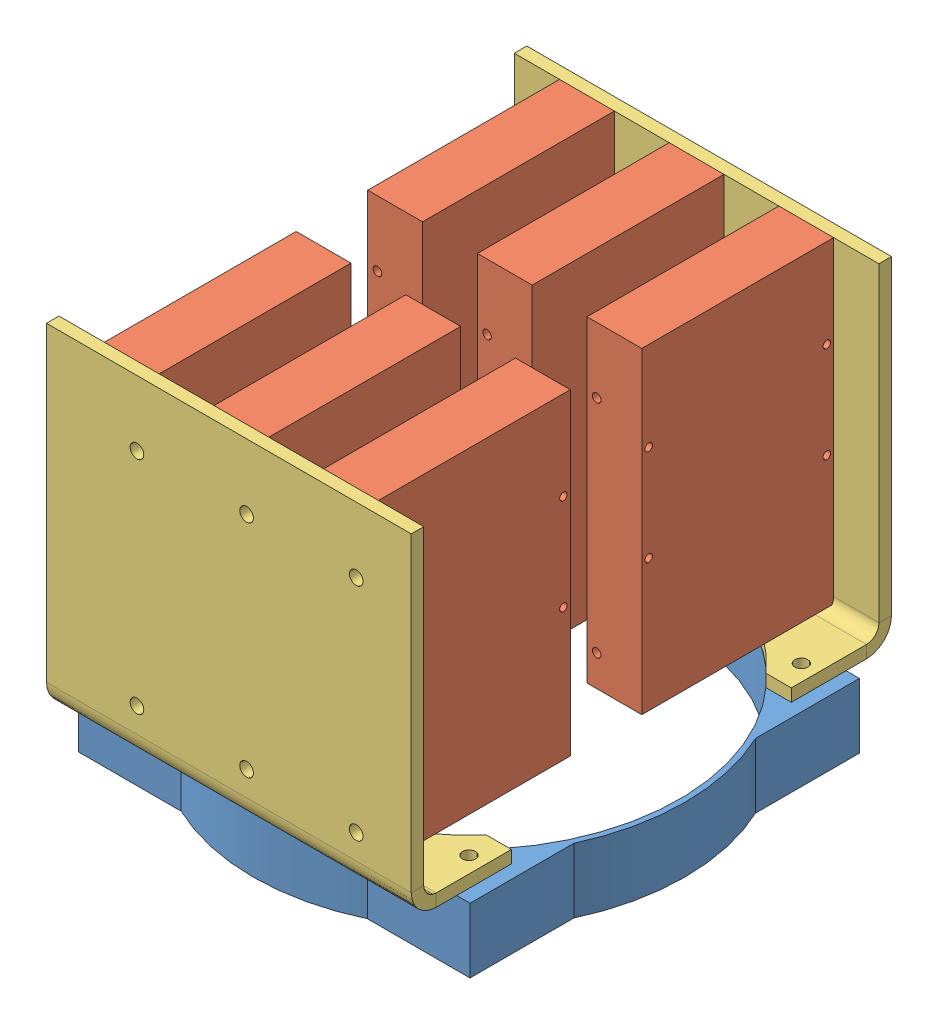
SolidWorks assembly final assembly, configuration Default. Lengths in mm.
Overall size (200 185.65 222.53).
11 component instances, 3 part files, 6 mates.
Components (placement in the parent):
- Fan blank-1: Fan blank [Default] at (-32.7187 -17.6847 29.2799) size (200 30 200)
- harddrive cady-1: harddrive cady [Default] at (12.2921 33.6612 44.8966) size (169 155.65 94.69)
  - harddrive blank-1: harddrive blank [Default] at (18.4892 60.8041 45.4069) x (0 0 1) z (0 -1 0) size (88.9 25.4 147)
  - caddy bracket-1: caddy bracket [Default] at (-45.0108 58.1041 89.8569) size (169 155.65 46.43)
  - harddrive blank-2: harddrive blank [Default] at (-32.3108 60.8041 45.4069) x (0 0 1) z (0 -1 0) size (88.9 25.4 147)
  - harddrive blank-3: harddrive blank [Default] at (-83.1108 60.8041 45.4069) x (0 0 1) z (0 -1 0) size (88.9 25.4 147)
- harddrive cady-2: harddrive cady [Default] at (-77.7295 33.6612 13.6633) x (-1 0 0) z (0 0 -1) size (169 155.65 94.69)
  - harddrive blank-1: harddrive blank [Default] at (18.4892 60.8041 45.4069) x (0 0 1) z (0 -1 0) size (88.9 25.4 147)
  - caddy bracket-1: caddy bracket [Default] at (-45.0108 58.1041 89.8569) size (169 155.65 46.43)
  - harddrive blank-2: harddrive blank [Default] at (-32.3108 60.8041 45.4069) x (0 0 1) z (0 -1 0) size (88.9 25.4 147)
  - harddrive blank-3: harddrive blank [Default] at (-83.1108 60.8041 45.4069) x (0 0 1) z (0 -1 0) size (88.9 25.4 147)
Mates (geometry in assembly coordinates):
- Concentric1: concentric aligned: circle of Fan blank-1; circle of harddrive cady-1/caddy bracket-1
- Concentric2: concentric aligned: circle of Fan blank-1; circle of harddrive cady-1/caddy bracket-1
- Coincident1: coincident anti-aligned: plane of Fan blank-1 through (-32.7187 12.3153 29.2799) normal (0 1 0); plane of harddrive cady-1/caddy bracket-1 through (51.7813 12.3153 94.1135) normal (0 -1 0)
- Concentric3: concentric aligned: circle of Fan blank-1; circle of harddrive cady-2/caddy bracket-1
- Concentric4: concentric aligned: circle of Fan blank-1; circle of harddrive cady-2/caddy bracket-1
- Coincident2: coincident anti-aligned: plane of Fan blank-1 through (-32.7187 12.3153 29.2799) normal (0 1 0); plane of harddrive cady-2/caddy bracket-1 through (-117.2187 12.3153 -35.5537) normal (0 -1 0)
